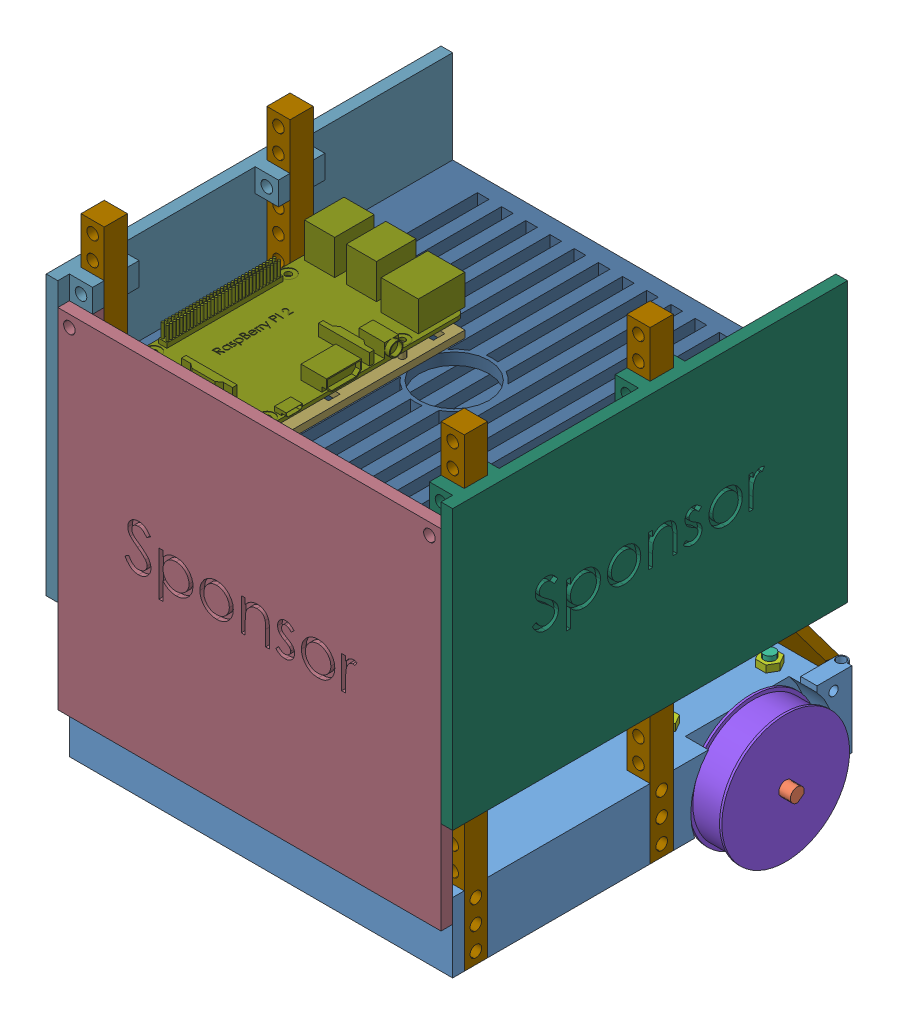
SolidWorks assembly base_robot2_assV4_mod, configuration Défaut. Lengths in mm.
Overall size (196.8 228.59 202.68).
45 component instances, 19 part files, 95 mates.
Components (placement in the parent):
- base_robot2_modelV3-1: base_robot2_modelV3 [Défaut] at (-7.2062 -14.7881 165) size (169 32.5 172.25)
- moteur_IG320100-1: moteur_IG320100 [Défaut] at (-74.68 -4.7881 115) x (0 0.840643 0.541589) z (-1 0 0) size (32 32 94.7)
- moteur_IG320100-2: moteur_IG320100 [Défaut] at (60.2677 -4.7881 115) x (0 -0.613287 0.789861) z (1 0 0) size (32 32 94.7)
- patin_robot2_model-1: patin_robot2_model [Défaut] at (-59.7062 -24.7881 217.5) size (40 10 30)
- patin_robot2_model-2: patin_robot2_model [Défaut] at (45.2938 -24.7881 217.5) size (40 10 30)
- support_moteur_30mm-1: support_moteur_30mm [Défaut] at (11.7938 -4.7881 115) x (1 0 0) z (0 0 -1) size (10 9 52.36)
- support_moteur_30mm-2: support_moteur_30mm [Défaut] at (-26.2062 -4.7881 115) x (-1 0 0) z (0 0 1) size (10 9 52.36)
- support_moteur_32.02mm-1: support_moteur_32.02mm [Défaut] at (61.7938 -4.7881 115) x (-1 0 0) z (0 0 1) size (10 10.01 55.01)
- support_moteur_32.02mm-2: support_moteur_32.02mm [Défaut] at (-76.2062 -4.7881 115) x (1 0 0) z (0 0 -1) size (10 10.01 55.01)
- vis_5mm-1: vis_5mm [Défaut] at (16.7938 -19.7881 93.8197) x (0.187636 0 -0.982239) z (-0.982239 0 -0.187636) size (8 42.5 8)
- vis_5mm-2: vis_5mm [Défaut] at (56.7938 -19.7881 92.4972) x (-0.262741 0 -0.964866) z (-0.964866 0 0.262741) size (8 42.5 8)
- vis_5mm-3: vis_5mm [Défaut] at (16.7938 -19.7881 136.1803) x (0.587771 0 -0.809028) z (-0.809028 0 -0.587771) size (8 42.5 8)
- vis_5mm-4: vis_5mm [Défaut] at (56.7938 -19.7881 137.5028) x (-0.993067 0 0.117546) z (0.117546 0 0.993067) size (8 42.5 8)
- vis_5mm-5: vis_5mm [Défaut] at (-31.2062 -19.7881 136.1803) x (0.909957 0 -0.414702) z (-0.414702 0 -0.909957) size (8 42.5 8)
- vis_5mm-6: vis_5mm [Défaut] at (-71.2062 -19.7881 137.5028) x (0.689074 0 -0.724691) z (-0.724691 0 -0.689074) size (8 42.5 8)
- vis_5mm-7: vis_5mm [Défaut] at (-31.2062 -19.7881 93.8197) x (0.478965 0 -0.877834) z (-0.877834 0 -0.478965) size (8 42.5 8)
- vis_5mm-8: vis_5mm [Défaut] at (-71.2062 -19.7881 92.4972) x (0.586817 0 -0.80972) z (-0.80972 0 -0.586817) size (8 42.5 8)
- vis_5mm-9: vis_5mm [Défaut] at (45.2938 -19.7881 217.5) x (0.470882 0 0.882196) z (0.882196 0 -0.470882) size (8 42.5 8)
- vis_5mm-10: vis_5mm [Défaut] at (-59.7062 -19.7881 217.5) x (-0.905597 0 -0.424138) z (-0.424138 0 0.905597) size (8 42.5 8)
- ecrou_5mm_model-1: ecrou_5mm_model [Défaut] at (56.7938 15.2119 92.4972) size (9 3 7.79)
- ecrou_5mm_model-2: ecrou_5mm_model [Défaut] at (-31.2062 15.2119 93.8197) size (9 3 7.79)
- ecrou_5mm_model-3: ecrou_5mm_model [Défaut] at (16.7938 15.2119 136.1803) size (9 3 7.79)
- ecrou_5mm_model-4: ecrou_5mm_model [Défaut] at (56.7938 15.2119 137.5028) size (9 3 7.79)
- ecrou_5mm_model-5: ecrou_5mm_model [Défaut] at (-31.2062 15.2119 136.1803) size (9 3 7.79)
- ecrou_5mm_model-6: ecrou_5mm_model [Défaut] at (16.7938 15.2119 93.8197) size (9 3 7.79)
- ecrou_5mm_model-7: ecrou_5mm_model [Défaut] at (-71.2062 15.2119 137.5028) size (9 3 7.79)
- ecrou_5mm_model-8: ecrou_5mm_model [Défaut] at (-71.2062 15.2119 92.4972) size (9 3 7.79)
- roue_imprimer_model-2: roue_imprimer_model [Défaut] at (-95.6062 -4.7881 115) x (1 0 0) z (0 0.840643 0.541589) size (15 55 55)
- roue_imprimer_model-3: roue_imprimer_model [Défaut] at (76.1938 -4.7881 115) x (1 0 0) z (0 0.613287 -0.789861) size (15 55 55)
- tige_robot2_model_V1-1: tige_robot2_model_V1 [Défaut] at (70.2938 85.2119 232.5) size (10 200 10)
- tige_robot2_model_V1-2: tige_robot2_model_V1 [Défaut] at (-84.7062 85.2119 232.5) size (10 200 10)
- tige_robot2_model_V1-3: tige_robot2_model_V1 [Défaut] at (70.2938 85.2119 152.5) size (10 200 10)
- tige_robot2_model_V1-4: tige_robot2_model_V1 [Défaut] at (-84.7062 85.2119 152.5) size (10 200 10)
- plaque_tige_robot2_V3_10mm-2: plaque_tige_robot2_V3_10mm [Défaut] at (-7.2062 115.2119 165) x (-1 0 0) z (0 0 -1) size (165 10 165)
- plaque_tige_robot2_V3_10mm-3: plaque_tige_robot2_V3_10mm [Défaut] at (-7.2062 55.2119 165) x (-1 0 0) z (0 0 -1) size (165 10 165)
- fixation_support_plaque-1: fixation_support_plaque [Défaut] at (-78.2711 120.2119 120.1336) x (0 0 1) z (0 1 0) size (11 11 14)
- fixation_support_plaque-2: fixation_support_plaque [Défaut] at (-72.7344 128.2119 135.4302) x (1 0 0) z (0 -1 0) size (11 11 14)
- support_raspberry_plaque_robot2_modelV1-2: support_raspberry_plaque_robot2_modelV1 [Défaut] at (-48.6384 125.2119 188.7251) x (0 0 -1) z (1 0 0) size (85 8 56)
- panneau_sponsor_robot2_150mm-1: panneau_sponsor_robot2_150mm [Défaut] at (-7.2062 80.2119 247.5) size (165 150 10)
- panneau_sponsor_robot2_gauche_120mm_model_V1-2: panneau_sponsor_robot2_gauche_120mm_model_V1 [Défaut] at (-89.7062 105.2119 167.5) x (0 0 1) z (-1 0 0) size (170 120 15)
- panneau_sponsor_robot2_droit_120mm_model_V1-2: panneau_sponsor_robot2_droit_120mm_model_V1 [Défaut] at (75.2938 105.2119 167.5) x (0 0 -1) z (1 0 0) size (170 120 15)
- raspberry-1: raspberry [Défaut] at (-48.6384 133.2119 188.8434) x (0 0 -1) z (1 0 0) size (89 17.6 58)
- arduino-1: arduino [Défaut] at (35.1773 70.2119 204.4796) x (0.009951 0 0.99995) z (-0.99995 0 0.009951) size (74.8 15.6 53.3)
- plaque_chasse_neige_robot2_model_D-1: plaque_chasse_neige_robot2_model_D [Défaut] at (-4.8077 0.2119 58.3124) x (-0.970019 0 -0.243031) z (0 1 0) size (87.5 10 40)
- plaque_chasse_neige_robot2_model_G-2: plaque_chasse_neige_robot2_model_G [Défaut] at (-9.5889 0.2119 58.3756) x (0.970216 0 -0.242241) z (0 -1 0) size (87.5 10 40)
Mates (geometry in assembly coordinates):
- Coaxiale1: concentric aligned: cylinder of base_robot2_modelV3-1 through (-52.7062 -4.7881 115) axis (-1 0 0) radius 16.01; cylinder of moteur_IG320100-1 through (-95.28 -4.7881 115) axis (-1 0 0) radius 16
- Coïncidente1: coincident anti-aligned: plane of base_robot2_modelV3-1 through (-52.7062 -4.7881 115) normal (-1 0 0); plane of moteur_IG320100-1 through (-52.7062 -4.7881 115) normal (1 0 0)
- Coaxiale3: concentric aligned: cylinder of base_robot2_modelV3-1 through (38.2938 -4.7881 115) axis (1 0 0) radius 16.01; cylinder of moteur_IG320100-2 through (80.8677 -4.7881 115) axis (1 0 0) radius 16
- Coïncidente2: coincident anti-aligned: plane of base_robot2_modelV3-1 through (38.2938 -4.7881 115) normal (1 0 0); plane of moteur_IG320100-2 through (38.2938 -4.7881 115) normal (-1 0 0)
- Coaxiale4: concentric aligned: cylinder of base_robot2_modelV3-1 through (-59.7062 15.2119 217.5) axis (0 -1 0) radius 2.5; cylinder of patin_robot2_model-1 through (-59.7062 -14.7881 217.5) axis (0 -1 0) radius 2.5
- Coaxiale5: concentric aligned: cylinder of base_robot2_modelV3-1 through (45.2938 15.2119 217.5) axis (0 -1 0) radius 2.5; cylinder of patin_robot2_model-2 through (45.2938 -14.7881 217.5) axis (0 -1 0) radius 2.5
- Coïncidente3: coincident anti-aligned: plane of base_robot2_modelV3-1 through (-7.2062 -14.7881 165) normal (0 -1 0); plane of patin_robot2_model-1 through (-59.7062 -14.7881 217.5) normal (0 1 0)
- Coïncidente4: coincident anti-aligned: plane of base_robot2_modelV3-1 through (-7.2062 -14.7881 165) normal (0 -1 0); plane of patin_robot2_model-2 through (45.2938 -14.7881 217.5) normal (0 1 0)
- Coaxiale6: concentric anti-aligned: cylinder of base_robot2_modelV3-1 through (16.7938 15.2119 93.8197) axis (0 -1 0) radius 2.5; cylinder of support_moteur_30mm-1 through (16.7938 -23.7881 93.8197) axis (0 1 0) radius 2.5
- Coaxiale7: concentric anti-aligned: cylinder of moteur_IG320100-2 through (80.8677 -4.7881 115) axis (1 0 0) radius 15; cylinder of support_moteur_30mm-1 through (21.7938 -4.7881 115) axis (-1 0 0) radius 15
- Coaxiale8: concentric anti-aligned: cylinder of base_robot2_modelV3-1 through (-31.2062 15.2119 93.8197) axis (0 -1 0) radius 2.5; cylinder of support_moteur_30mm-2 through (-31.2062 -23.7881 93.8197) axis (0 1 0) radius 2.5
- Coaxiale9: concentric anti-aligned: cylinder of moteur_IG320100-1 through (-95.28 -4.7881 115) axis (-1 0 0) radius 15; cylinder of support_moteur_30mm-2 through (-36.2062 -4.7881 115) axis (1 0 0) radius 15
- Coaxiale10: concentric anti-aligned: cylinder of base_robot2_modelV3-1 through (56.7938 15.2119 92.4972) axis (0 -1 0) radius 2.5; cylinder of support_moteur_32.02mm-1 through (56.7938 -24.7981 92.4972) axis (0 1 0) radius 2.5
- Coaxiale12: concentric aligned: cylinder of moteur_IG320100-2 through (80.8677 -4.7881 115) axis (1 0 0) radius 16; cylinder of support_moteur_32.02mm-1 through (51.7938 -4.7881 115) axis (1 0 0) radius 16.01
- Coaxiale13: concentric aligned: cylinder of moteur_IG320100-1 through (-95.28 -4.7881 115) axis (-1 0 0) radius 16; cylinder of support_moteur_32.02mm-2 through (-66.2062 -4.7881 115) axis (-1 0 0) radius 16.01
- Coaxiale14: concentric anti-aligned: cylinder of base_robot2_modelV3-1 through (-71.2062 15.2119 137.5028) axis (0 -1 0) radius 2.5; cylinder of support_moteur_32.02mm-2 through (-71.2062 -24.7981 137.5028) axis (0 1 0) radius 2.5
- Coaxiale16: concentric aligned: cylinder of base_robot2_modelV3-1 through (16.7938 15.2119 93.8197) axis (0 -1 0) radius 2.5; cylinder of vis_5mm-1 through (16.7938 20.2119 93.8197) axis (0 -1 0) radius 2.5
- Coïncidente6: coincident anti-aligned: plane of support_moteur_30mm-1 through (21.7938 -19.7881 115) normal (0 -1 0); plane of vis_5mm-1 through (16.7938 -19.7881 93.8197) normal (0 1 0)
- Coaxiale17: concentric aligned: cylinder of base_robot2_modelV3-1 through (56.7938 15.2119 92.4972) axis (0 -1 0) radius 2.5; cylinder of vis_5mm-2 through (56.7938 20.2119 92.4972) axis (0 -1 0) radius 2.5
- Coïncidente7: coincident anti-aligned: plane of support_moteur_32.02mm-1 through (51.7938 -19.7881 87.4972) normal (0 -1 0); plane of vis_5mm-2 through (56.7938 -19.7881 92.4972) normal (0 1 0)
- Coaxiale18: concentric anti-aligned: cylinder of support_moteur_32.02mm-1 through (56.7938 -24.7981 137.5028) axis (0 1 0) radius 2.5; cylinder of vis_5mm-4 through (56.7938 20.2119 137.5028) axis (0 -1 0) radius 2.5
- Coïncidente8: coincident anti-aligned: plane of support_moteur_32.02mm-1 through (51.7938 -19.7881 142.5028) normal (0 -1 0); plane of vis_5mm-4 through (56.7938 -19.7881 137.5028) normal (0 1 0)
- Coaxiale20: concentric anti-aligned: cylinder of support_moteur_30mm-1 through (16.7938 -23.7881 136.1803) axis (0 1 0) radius 2.5; cylinder of vis_5mm-3 through (16.7938 20.2119 136.1803) axis (0 -1 0) radius 2.5
- Coïncidente9: coincident anti-aligned: plane of support_moteur_30mm-1 through (21.7938 -19.7881 115) normal (0 -1 0); plane of vis_5mm-3 through (16.7938 -19.7881 136.1803) normal (0 1 0)
- Coaxiale21: concentric anti-aligned: cylinder of support_moteur_30mm-2 through (-31.2062 -23.7881 93.8197) axis (0 1 0) radius 2.5; cylinder of vis_5mm-7 through (-31.2062 20.2119 93.8197) axis (0 -1 0) radius 2.5
- Coaxiale22: concentric anti-aligned: cylinder of support_moteur_32.02mm-2 through (-71.2062 -24.7981 92.4972) axis (0 1 0) radius 2.5; cylinder of vis_5mm-8 through (-71.2062 20.2119 92.4972) axis (0 -1 0) radius 2.5
- Coaxiale23: concentric anti-aligned: cylinder of support_moteur_32.02mm-2 through (-71.2062 -24.7981 137.5028) axis (0 1 0) radius 2.5; cylinder of vis_5mm-6 through (-71.2062 20.2119 137.5028) axis (0 -1 0) radius 2.5
- Coaxiale24: concentric anti-aligned: cylinder of support_moteur_30mm-2 through (-31.2062 -23.7881 136.1803) axis (0 1 0) radius 2.5; cylinder of vis_5mm-5 through (-31.2062 20.2119 136.1803) axis (0 -1 0) radius 2.5
- Coïncidente10: coincident anti-aligned: plane of support_moteur_30mm-2 through (-36.2062 -19.7881 115) normal (0 -1 0); plane of vis_5mm-5 through (-31.2062 -19.7881 136.1803) normal (0 1 0)
- Coïncidente11: coincident anti-aligned: plane of support_moteur_32.02mm-2 through (-66.2062 -19.7881 142.5028) normal (0 -1 0); plane of vis_5mm-6 through (-71.2062 -19.7881 137.5028) normal (0 1 0)
- Coïncidente12: coincident anti-aligned: plane of support_moteur_32.02mm-2 through (-66.2062 -19.7881 87.4972) normal (0 -1 0); plane of vis_5mm-8 through (-71.2062 -19.7881 92.4972) normal (0 1 0)
- Coïncidente13: coincident anti-aligned: plane of support_moteur_30mm-2 through (-36.2062 -19.7881 115) normal (0 -1 0); plane of vis_5mm-7 through (-31.2062 -19.7881 93.8197) normal (0 1 0)
- Coaxiale25: concentric aligned: cylinder of base_robot2_modelV3-1 through (45.2938 15.2119 217.5) axis (0 -1 0) radius 2.5; cylinder of vis_5mm-9 through (45.2938 20.2119 217.5) axis (0 -1 0) radius 2.5
- Coïncidente14: coincident anti-aligned: plane of patin_robot2_model-2 through (45.2938 -19.7881 217.5) normal (0 -1 0); plane of vis_5mm-9 through (45.2938 -19.7881 217.5) normal (0 1 0)
- Coaxiale26: concentric aligned: cylinder of base_robot2_modelV3-1 through (-59.7062 15.2119 217.5) axis (0 -1 0) radius 2.5; cylinder of vis_5mm-10 through (-59.7062 20.2119 217.5) axis (0 -1 0) radius 2.5
- Coïncidente15: coincident anti-aligned: plane of patin_robot2_model-1 through (-59.7062 -19.7881 217.5) normal (0 -1 0); plane of vis_5mm-10 through (-59.7062 -19.7881 217.5) normal (0 1 0)
- Coaxiale27: concentric aligned: cylinder of vis_5mm-2 through (56.7938 20.2119 92.4972) axis (0 -1 0) radius 2.5; cylinder of ecrou_5mm_model-1 through (56.7938 18.2119 92.4972) axis (0 -1 0) radius 2.5
- Coïncidente16: coincident anti-aligned: plane of base_robot2_modelV3-1 through (-7.2062 15.2119 165) normal (0 1 0); plane of ecrou_5mm_model-1 through (56.7938 15.2119 92.4972) normal (0 -1 0)
- Coaxiale30: concentric aligned: cylinder of vis_5mm-4 through (56.7938 20.2119 137.5028) axis (0 -1 0) radius 2.5; cylinder of ecrou_5mm_model-4 through (56.7938 18.2119 137.5028) axis (0 -1 0) radius 2.5
- Coaxiale31: concentric aligned: cylinder of vis_5mm-3 through (16.7938 20.2119 136.1803) axis (0 -1 0) radius 2.5; cylinder of ecrou_5mm_model-3 through (16.7938 18.2119 136.1803) axis (0 -1 0) radius 2.5
- Coaxiale32: concentric aligned: cylinder of vis_5mm-1 through (16.7938 20.2119 93.8197) axis (0 -1 0) radius 2.5; cylinder of ecrou_5mm_model-6 through (16.7938 18.2119 93.8197) axis (0 -1 0) radius 2.5
- Coaxiale33: concentric aligned: cylinder of vis_5mm-8 through (-71.2062 20.2119 92.4972) axis (0 -1 0) radius 2.5; cylinder of ecrou_5mm_model-8 through (-71.2062 18.2119 92.4972) axis (0 -1 0) radius 2.5
- Coïncidente19: coincident anti-aligned: cylinder of vis_5mm-6 through (-71.2062 20.2119 137.5028) axis (0 -1 0) radius 2.5; circle of ecrou_5mm_model-7
- Coaxiale34: concentric aligned: cylinder of vis_5mm-5 through (-31.2062 20.2119 136.1803) axis (0 -1 0) radius 2.5; cylinder of ecrou_5mm_model-5 through (-31.2062 18.2119 136.1803) axis (0 -1 0) radius 2.5
- Coaxiale35: concentric aligned: cylinder of vis_5mm-7 through (-31.2062 20.2119 93.8197) axis (0 -1 0) radius 2.5; cylinder of ecrou_5mm_model-2 through (-31.2062 18.2119 93.8197) axis (0 -1 0) radius 2.5
- Coïncidente20: coincident anti-aligned: plane of base_robot2_modelV3-1 through (-7.2062 15.2119 165) normal (0 1 0); plane of ecrou_5mm_model-4 through (56.7938 15.2119 137.5028) normal (0 -1 0)
- Coïncidente21: coincident anti-aligned: plane of base_robot2_modelV3-1 through (-7.2062 15.2119 165) normal (0 1 0); plane of ecrou_5mm_model-6 through (16.7938 15.2119 93.8197) normal (0 -1 0)
- Coïncidente22: coincident anti-aligned: plane of base_robot2_modelV3-1 through (-7.2062 15.2119 165) normal (0 1 0); plane of ecrou_5mm_model-3 through (16.7938 15.2119 136.1803) normal (0 -1 0)
- Coïncidente23: coincident anti-aligned: plane of base_robot2_modelV3-1 through (-7.2062 15.2119 165) normal (0 1 0); plane of ecrou_5mm_model-5 through (-31.2062 15.2119 136.1803) normal (0 -1 0)
- Coïncidente24: coincident anti-aligned: plane of base_robot2_modelV3-1 through (-7.2062 15.2119 165) normal (0 1 0); plane of ecrou_5mm_model-8 through (-71.2062 15.2119 92.4972) normal (0 -1 0)
- Coïncidente25: coincident anti-aligned: plane of base_robot2_modelV3-1 through (-7.2062 15.2119 165) normal (0 1 0); plane of ecrou_5mm_model-2 through (-31.2062 15.2119 93.8197) normal (0 -1 0)
- Coïncidente26: coincident anti-aligned: plane of base_robot2_modelV3-1 through (-7.2062 15.2119 165) normal (0 1 0); plane of ecrou_5mm_model-7 through (-71.2062 15.2119 137.5028) normal (0 -1 0)
- Coaxiale36: concentric anti-aligned: cylinder of moteur_IG320100-1 through (-95.28 -4.7881 115) axis (-1 0 0) radius 3; cylinder of roue_imprimer_model-2 through (-100.6062 -4.7881 115) axis (1 0 0) radius 3
- Coïncidente27: coincident anti-aligned: plane of moteur_IG320100-1 through (-93.6062 -4.8281 112.0003) normal (0 0.541589 -0.840643); plane of roue_imprimer_model-2 through (-100.6062 -2.04 113.7965) normal (0 -0.541589 0.840643)
- Distance1: distance = 5 mm aligned: plane of moteur_IG320100-1 through (-105.6062 -4.7881 115) normal (-1 0 0); plane of roue_imprimer_model-2 through (-100.6062 -4.7881 115) normal (-1 0 0)
- Coïncidente29: coincident anti-aligned: plane of moteur_IG320100-2 through (79.1938 -5.7457 112.1569) normal (0 -0.789861 -0.613287); plane of roue_imprimer_model-3 through (71.1938 -5.7457 112.1569) normal (0 0.789861 0.613287)
- Coaxiale37: concentric aligned: cylinder of moteur_IG320100-2 through (80.8677 -4.7881 115) axis (1 0 0) radius 3; cylinder of roue_imprimer_model-3 through (71.1938 -4.7881 115) axis (1 0 0) radius 3
- Distance2: distance = 5 mm aligned: plane of roue_imprimer_model-3 through (86.1938 -4.7881 115) normal (1 0 0); plane of moteur_IG320100-2 through (91.1938 -4.7881 115) normal (1 0 0)
- Coaxiale40: concentric anti-aligned: cylinder of base_robot2_modelV3-1 through (-91.7072 10.2119 237.5) axis (1 0 0) radius 2.5; cylinder of tige_robot2_model_V1-1 through (75.2938 10.2119 237.5) axis (-1 0 0) radius 2.5
- Coaxiale41: concentric anti-aligned: cylinder of base_robot2_modelV3-1 through (-91.7072 -9.7881 237.5) axis (1 0 0) radius 2.5; cylinder of tige_robot2_model_V1-1 through (75.2938 -9.7881 237.5) axis (-1 0 0) radius 2.5
- Coïncidente32: coincident anti-aligned: plane of base_robot2_modelV3-1 through (65.2938 -14.7881 165) normal (1 0 0); plane of tige_robot2_model_V1-1 through (65.2938 185.2119 242.5) normal (-1 0 0)
- Coaxiale42: concentric anti-aligned: cylinder of base_robot2_modelV3-1 through (-91.7072 10.2119 157.5) axis (1 0 0) radius 2.5; cylinder of tige_robot2_model_V1-3 through (75.2938 10.2119 157.5) axis (-1 0 0) radius 2.5
- Coaxiale43: concentric anti-aligned: cylinder of base_robot2_modelV3-1 through (-91.7072 -9.7881 157.5) axis (1 0 0) radius 2.5; cylinder of tige_robot2_model_V1-3 through (75.2938 -9.7881 157.5) axis (-1 0 0) radius 2.5
- Coïncidente33: coincident anti-aligned: plane of base_robot2_modelV3-1 through (65.2938 -14.7881 165) normal (1 0 0); plane of tige_robot2_model_V1-3 through (65.2938 185.2119 162.5) normal (-1 0 0)
- Coaxiale44: concentric anti-aligned: cylinder of base_robot2_modelV3-1 through (-91.7072 10.2119 237.5) axis (1 0 0) radius 2.5; cylinder of tige_robot2_model_V1-2 through (-79.7062 10.2119 237.5) axis (-1 0 0) radius 2.5
- Coaxiale45: concentric anti-aligned: cylinder of base_robot2_modelV3-1 through (-91.7072 -9.7881 237.5) axis (1 0 0) radius 2.5; cylinder of tige_robot2_model_V1-2 through (-79.7062 -9.7881 237.5) axis (-1 0 0) radius 2.5
- Coïncidente34: coincident anti-aligned: plane of base_robot2_modelV3-1 through (-79.7062 -14.7881 165) normal (-1 0 0); plane of tige_robot2_model_V1-2 through (-79.7062 185.2119 242.5) normal (1 0 0)
- Coaxiale46: concentric anti-aligned: cylinder of base_robot2_modelV3-1 through (-91.7072 10.2119 157.5) axis (1 0 0) radius 2.5; cylinder of tige_robot2_model_V1-4 through (-79.7062 10.2119 157.5) axis (-1 0 0) radius 2.5
- Coaxiale47: concentric anti-aligned: cylinder of base_robot2_modelV3-1 through (-91.7072 -9.7881 157.5) axis (1 0 0) radius 2.5; cylinder of tige_robot2_model_V1-4 through (-79.7062 -9.7881 157.5) axis (-1 0 0) radius 2.5
- Coïncidente35: coincident anti-aligned: plane of base_robot2_modelV3-1 through (-79.7062 -14.7881 165) normal (-1 0 0); plane of tige_robot2_model_V1-4 through (-79.7062 185.2119 162.5) normal (1 0 0)
- Coaxiale48: concentric anti-aligned: cylinder of tige_robot2_model_V1-3 through (70.2938 60.2119 162.5) axis (0 0 -1) radius 2.5; cylinder of plaque_tige_robot2_V3_10mm-3 through (70.2938 60.2119 82.5) axis (0 0 1) radius 2.5
- Coaxiale49: concentric anti-aligned: cylinder of tige_robot2_model_V1-2 through (-84.7062 60.2119 242.5) axis (0 0 -1) radius 2.5; cylinder of plaque_tige_robot2_V3_10mm-3 through (-84.7062 60.2119 82.5) axis (0 0 1) radius 2.5
- Coïncidente37: coincident anti-aligned: plane of tige_robot2_model_V1-2 through (-84.7062 85.2119 242.5) normal (0 0 1); plane of plaque_tige_robot2_V3_10mm-3 through (-7.2062 65.2119 242.5) normal (0 0 -1)
- Coïncidente38: coincident anti-aligned: plane of tige_robot2_model_V1-2 through (-84.7062 85.2119 242.5) normal (0 0 1); plane of plaque_tige_robot2_V3_10mm-2 through (-7.2062 125.2119 242.5) normal (0 0 -1)
- Distance3: distance = 5 mm anti-aligned: plane of arduino-1 through (35.1773 70.2119 204.4796) normal (0 -1 0); plane of plaque_tige_robot2_V3_10mm-3 through (-7.2062 65.2119 165) normal (0 1 0)
- Coaxiale51: concentric aligned: cylinder of tige_robot2_model_V1-2 through (-84.7062 150.2119 242.5) axis (0 0 -1) radius 2.5; cylinder of panneau_sponsor_robot2_150mm-1 through (-84.7062 150.2119 252.5) axis (0 0 -1) radius 2.5
- Coïncidente39: coincident anti-aligned: plane of tige_robot2_model_V1-2 through (-84.7062 85.2119 242.5) normal (0 0 1); plane of panneau_sponsor_robot2_150mm-1 through (-89.7062 145.2119 242.5) normal (0 0 -1)
- Coïncidente40: coincident anti-aligned: plane of plaque_tige_robot2_V3_10mm-2 through (-89.7062 125.2119 165) normal (-1 0 0); plane of panneau_sponsor_robot2_gauche_120mm_model_V1-2 through (-89.7062 105.2119 167.5) normal (1 0 0)
- Coïncidente41: coincident anti-aligned: plane of tige_robot2_model_V1-2 through (-84.7062 85.2119 232.5) normal (0 0 -1); plane of panneau_sponsor_robot2_gauche_120mm_model_V1-2 through (-89.7062 155.2119 232.5) normal (0 0 1)
- Coaxiale54: concentric anti-aligned: cylinder of tige_robot2_model_V1-2 through (-84.7062 160.2119 242.5) axis (0 0 -1) radius 2.5; cylinder of panneau_sponsor_robot2_gauche_120mm_model_V1-2 through (-84.7062 160.2119 82.5) axis (0 0 1) radius 2.5
- Coaxiale55: concentric anti-aligned: cylinder of tige_robot2_model_V1-4 through (-84.7062 160.2119 162.5) axis (0 0 -1) radius 2.5; cylinder of panneau_sponsor_robot2_gauche_120mm_model_V1-2 through (-84.7062 160.2119 82.5) axis (0 0 1) radius 2.5
- Coaxiale56: concentric aligned: cylinder of tige_robot2_model_V1-1 through (70.2938 160.2119 242.5) axis (0 0 -1) radius 2.5; cylinder of panneau_sponsor_robot2_droit_120mm_model_V1-2 through (70.2938 160.2119 252.5) axis (0 0 -1) radius 2.5
- Coïncidente42: coincident anti-aligned: plane of tige_robot2_model_V1-1 through (70.2938 85.2119 242.5) normal (0 0 1); plane of panneau_sponsor_robot2_droit_120mm_model_V1-2 through (75.2938 155.2119 242.5) normal (0 0 -1)
- Coïncidente43: coincident anti-aligned: plane of tige_robot2_model_V1-3 through (75.2938 185.2119 162.5) normal (1 0 0); plane of panneau_sponsor_robot2_droit_120mm_model_V1-2 through (75.2938 105.2119 167.5) normal (-1 0 0)
- Coaxiale57: concentric anti-aligned: cylinder of tige_robot2_model_V1-1 through (70.2938 120.2119 242.5) axis (0 0 -1) radius 2.5; circle of tige_robot2_model_V1-3
- Coaxiale58: concentric anti-aligned: cylinder of tige_robot2_model_V1-4 through (-84.7062 120.2119 162.5) axis (0 0 -1) radius 2.5; cylinder of plaque_tige_robot2_V3_10mm-2 through (-84.7062 120.2119 82.5) axis (0 0 1) radius 2.5
- Coïncidente49: coincident: plane of plaque_tige_robot2_V3_10mm-2 through (-40.9562 125.2119 165) normal (1 0 0); line of fixation_support_plaque-2 through (-40.9562 128.7119 153.9118) axis (0 -1 0)
- Coïncidente52: coincident anti-aligned: plane of plaque_tige_robot2_V3_10mm-2 through (-56.7895 125.2119 165) normal (-1 0 0); plane of fixation_support_plaque-1 through (-56.7895 128.2119 151.9118) normal (1 0 0)
- Coïncidente53: coincident anti-aligned: plane of plaque_tige_robot2_V3_10mm-2 through (-7.2062 125.2119 165) normal (0 1 0); plane of support_raspberry_plaque_robot2_modelV1-2 through (-48.6384 125.2119 188.7251) normal (0 -1 0)
- Coaxiale59: concentric aligned: cylinder of raspberry-1 through (-24.1384 134.8119 227.8434) axis (0 -1 0) radius 1.375; cylinder of support_raspberry_plaque_robot2_modelV1-2 through (-24.1384 133.2119 227.8434) axis (0 -1 0) radius 1.375
- Coïncidente55: coincident anti-aligned: plane of fixation_support_plaque-2 through (-40.9562 120.2119 151.9118) normal (0 0 -1); plane of support_raspberry_plaque_robot2_modelV1-2 through (-73.6384 128.2119 151.9118) normal (0 0 1)
- Coaxiale60: concentric anti-aligned: cylinder of base_robot2_modelV3-1 through (72.7938 -4.7881 77.7549) axis (0 -1 0) radius 2; cylinder of plaque_chasse_neige_robot2_model_D-1 through (72.7938 -4.7881 77.7549) axis (0 1 0) radius 2
- Coïncidente56: coincident anti-aligned: plane of base_robot2_modelV3-1 through (-7.2062 5.2119 165) normal (0 -1 0); plane of plaque_chasse_neige_robot2_model_D-1 through (72.7938 5.2119 77.7549) normal (0 1 0)
- Coaxiale61: concentric aligned: cylinder of base_robot2_modelV3-1 through (-87.2062 -4.7881 77.7549) axis (0 -1 0) radius 2; cylinder of plaque_chasse_neige_robot2_model_G-2 through (-87.2062 5.2119 77.7549) axis (0 -1 0) radius 2
- Coïncidente57: coincident anti-aligned: plane of base_robot2_modelV3-1 through (-7.2062 5.2119 165) normal (0 -1 0); plane of plaque_chasse_neige_robot2_model_G-2 through (-87.2062 5.2119 77.7549) normal (0 1 0)
